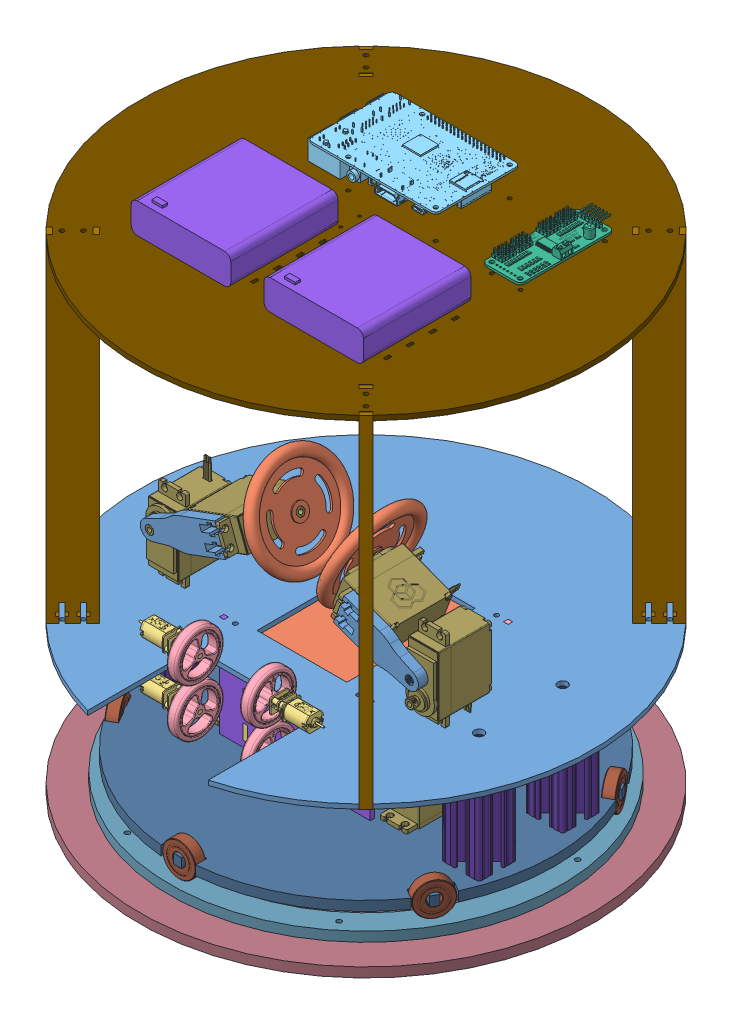
SolidWorks assembly Big_assembly, configuration Default. Lengths in mm.
Overall size (883.19 344.85 416.68).
60 component instances, 26 part files, 69 mates.
Components (placement in the parent):
- Top_Plate-1: Top_Plate [Default] at (43.1232 135.9669 213.6258) size (300 3 294.57)
- Deck-1: Deck [Default] at (43.1232 119.9669 213.6258) size (883.19 16 224.45)
- wall_long_side-1: wall_long_side [Default] at (11.6232 103.9669 213.6258) x (0 0 1) z (-1 0 0) size (94.4 64 3)
- wall_long_side-2: wall_long_side [Default] at (77.6232 103.9669 213.6258) x (0 0 1) z (-1 0 0) size (94.4 64 3)
- wall_back-1: wall_back [Default] at (43.1232 103.9669 166.4258) x (0 0 1) z (-1 0 0) size (3 67 100)
- box_bottom-1: box_bottom [Default] at (43.1232 81.8367 213.6258) size (87.5 3 88)
- Spring-1: Spring [Default] at (81.3732 96.1631 233.6258) size (7.89 47.53 7.89)
- 92125A130_TYPE 18-8 SS FLAT-HEAD SOCKET CAP SCREW-1: 92125A130_TYPE 18-8 SS FLAT-HEAD SOCKET CAP SCREW [92125A130] at (74.6232 132.4669 233.6258) x (0 -0.041478 -0.999139) z (-1 0 0) size (6 6 10.3)
- Spring-2: Spring [Default] at (4.3732 96.1631 233.6258) size (7.89 47.53 7.89)
- Spring-3: Spring [Default] at (81.3732 96.1631 193.6258) size (7.89 47.53 7.89)
- Spring-4: Spring [Default] at (4.3732 96.1631 193.6258) size (7.89 47.53 7.89)
- 92125A130_TYPE 18-8 SS FLAT-HEAD SOCKET CAP SCREW-2: 92125A130_TYPE 18-8 SS FLAT-HEAD SOCKET CAP SCREW [92125A130] at (74.6232 132.4669 193.6258) x (0 -0.041478 -0.999139) z (-1 0 0) size (6 6 10.3)
- 92125A130_TYPE 18-8 SS FLAT-HEAD SOCKET CAP SCREW-3: 92125A130_TYPE 18-8 SS FLAT-HEAD SOCKET CAP SCREW [92125A130] at (11.6232 132.4669 233.6258) x (0 0.041478 0.999139) z (1 0 0) size (6 6 10.3)
- 92125A130_TYPE 18-8 SS FLAT-HEAD SOCKET CAP SCREW-4: 92125A130_TYPE 18-8 SS FLAT-HEAD SOCKET CAP SCREW [92125A130] at (11.6232 132.4669 193.6258) x (0 0.041478 0.999139) z (1 0 0) size (6 6 10.3)
- wall_front_v02-1: wall_front_v02 [Default] at (43.1232 103.9669 260.8258) x (0 0 -1) z (1 0 0) size (3 67 100)
- 220_x_40mm_vertical_beam_1-4_in_t-slots-1: 220_x_40mm_vertical_beam_1-4_in_t-slots [Default] at (129.2665 138.9669 122.9924) x (0.707107 0 -0.707107) z (0 -1 0) size (25 6.35 226)
- assem3-1: assem3 [Default] at (169.2489 77.438 270.0894) x (0.934159 0 0.356856) z (-0.356856 0 0.934159) size (322.75 56.87 322.75)
  - lazy_susan_protoype-1: lazy_susan_protoype [Default] at (-137.9709 -17.8212 -7.7373) x (0.356856 0 0.934159) z (-0.934159 0 0.356856) size (250 6.35 250)
  - 5972K501_BALL BEARING-1: 5972K501_BALL BEARING [5972K501] at (-61.9864 -14.6462 -101.2605) x (-0.500804 -0.763962 -0.406887) z (-0.630577 0 0.776126) size (22 22 7)
  - servo-1: servo [Default] at (-83.0236 -8.9712 -18.0228) x (-0.934159 0 0.356856) z (0.356856 0 0.934159) size (20 45.1 60)
  - servo-2: servo [Default] at (-185.7811 -8.9712 21.2314) x (-0.934159 0 0.356856) z (0.356856 0 0.934159) size (20 45.1 60)
  - 5972K501_BALL BEARING-5: 5972K501_BALL BEARING [5972K501] at (-18.9852 -14.6462 11.3057) x (0.101972 -0.763962 -0.637152) z (-0.987434 0 -0.158033) size (22 22 7)
  - 5972K501_BALL BEARING-6: 5972K501_BALL BEARING [5972K501] at (-94.9697 -14.6462 104.8289) x (0.602776 -0.763962 -0.230265) z (-0.356856 0 -0.934159) size (22 22 7)
  - 5972K501_BALL BEARING-7: 5972K501_BALL BEARING [5972K501] at (-213.9555 -14.6462 85.786) x (0.500804 -0.763962 0.406887) z (0.630577 0 -0.776126) size (22 22 7)
  - base-1: base [Default] at (-137.9709 -38.3462 -7.7373) size (300 6.35 300)
  - new_rail-1: new_rail [Default] at (-137.9709 -31.9962 -7.7373) size (260 6.35 260)
  - new_base_gear-1: new_base_gear [Default] at (-137.9709 -30.0764 -7.7373) x (0 0 -1) z (0 1 0) size (59.22 59.28 6.35)
  - new_servo_gear-1: new_servo_gear [Default] at (-189.3497 -28.8212 11.8898) x (0.783336 0 0.621598) z (0 1 0) size (59.22 59.28 6.35)
  - new_servo_gear-2: new_servo_gear [Default] at (-86.5922 -27.8212 -27.3644) x (0.136575 0 0.99063) z (0 1 0) size (59.22 59.28 6.35)
  - 5972K501_BALL BEARING-8: 5972K501_BALL BEARING [5972K501] at (-256.9567 -14.6462 -26.7802) x (-0.101972 -0.763962 0.637152) z (0.987434 0 0.158033) size (22 22 7)
  - 5972K501_BALL BEARING-9: 5972K501_BALL BEARING [5972K501] at (-180.9721 -14.6462 -120.3035) x (-0.602776 -0.763962 0.230265) z (0.356856 0 0.934159) size (22 22 7)
- 47065T411_ALUMINUM T-SLOTTED FRAMING EXTRUSION-1: 47065T411_ALUMINUM T-SLOTTED FRAMING EXTRUSION [47065T411] at (-59.5768 100.9669 185.9258) x (1 0 0) z (0 -1 0) size (25.4 25.4 70)
- 47065T411_ALUMINUM T-SLOTTED FRAMING EXTRUSION-4: 47065T411_ALUMINUM T-SLOTTED FRAMING EXTRUSION [47065T411] at (-59.5768 100.9669 241.3258) x (1 0 0) z (0 1 0) size (25.4 25.4 70)
- 47065T411_ALUMINUM T-SLOTTED FRAMING EXTRUSION-5: 47065T411_ALUMINUM T-SLOTTED FRAMING EXTRUSION [47065T411] at (145.8232 100.9669 241.3258) x (-1 0 0) z (0 -1 0) size (25.4 25.4 70)
- 47065T411_ALUMINUM T-SLOTTED FRAMING EXTRUSION-6: 47065T411_ALUMINUM T-SLOTTED FRAMING EXTRUSION [47065T411] at (145.8232 100.9669 185.9258) x (-1 0 0) z (0 1 0) size (25.4 25.4 70)
- 220_x_40mm_vertical_beam_1-4_in_t-slots-2: 220_x_40mm_vertical_beam_1-4_in_t-slots [Default] at (133.7566 138.9669 299.7691) x (0.707107 0 0.707107) z (0 -1 0) size (25 6.35 226)
- 220_x_40mm_vertical_beam_1-4_in_t-slots-3: 220_x_40mm_vertical_beam_1-4_in_t-slots [Default] at (-43.0201 138.9669 304.2592) x (-0.707107 0 0.707107) z (0 -1 0) size (25 6.35 226)
- 220_x_40mm_vertical_beam_1-4_in_t-slots-4: 220_x_40mm_vertical_beam_1-4_in_t-slots [Default] at (-47.5102 138.9669 127.4825) x (-0.707107 0 -0.707107) z (0 -1 0) size (25 6.35 226)
- electronics_mount_2-1: electronics_mount_2 [Default] at (-62.9428 358.9669 319.6918) size (300 3.17 300)
- servo-1: servo [Default] at (-43.0683 165.9669 253.4758) x (1 0 0) z (0 -1 0) size (20 45.1 60)
- servo_to_servo_horn-1: servo_to_servo_horn [Default] at (-43.0683 175.9669 264.7258) x (0.937047 0.349203 0) z (0.349203 -0.937047 0) size (56 6.35 20)
- servo-2: servo [Default] at (3.7841 193.427 244.0758) x (0.349203 -0.937047 0) z (0 0 1) size (20 45.1 60)
- 2_5_8_plastic_blue_wheel_futaba_servo_hub-1: 2_5_8_plastic_blue_wheel_futaba_servo_hub [Default] at (18.7909 199.0195 234.0758) x (0.220834 -0.592585 -0.774645) z (-0.937047 -0.349203 0) size (66.67 66.67 7.62)
- micro-metal-gearmotor-backshaft-1: micro-metal-gearmotor-backshaft [Default] at (3.1232 151.9669 302.5558) x (0 0 -1) z (1 0 0) size (12 10.04 40.2)
- pololu-wheel-32x7mm-black-1: pololu-wheel-32x7mm-black [Default] at (18.8232 151.9669 302.5558) x (0 0 -1) z (1 0 0) size (32 32 8.6)
- pololu-wheel-32x7mm-black-2: pololu-wheel-32x7mm-black [Default] at (18.8232 119.9669 302.5558) x (0 0 -1) z (1 0 0) size (32 32 8.6)
- micro-metal-gearmotor-backshaft-2: micro-metal-gearmotor-backshaft [Default] at (3.1232 119.9669 302.5558) x (0 0 -1) z (1 0 0) size (12 10.04 40.2)
- pololu-wheel-32x7mm-black-3: pololu-wheel-32x7mm-black [Default] at (67.4232 151.9669 302.5558) x (0 0 1) z (-1 0 0) size (32 32 8.6)
- micro-metal-gearmotor-backshaft-3: micro-metal-gearmotor-backshaft [Default] at (83.1232 151.9669 302.5558) x (0 0 1) z (-1 0 0) size (12 10.04 40.2)
- pololu-wheel-32x7mm-black-4: pololu-wheel-32x7mm-black [Default] at (67.4232 119.9669 302.5558) x (0 0 1) z (-1 0 0) size (32 32 8.6)
- micro-metal-gearmotor-backshaft-4: micro-metal-gearmotor-backshaft [Default] at (83.1232 119.9669 302.5558) x (0 0 1) z (-1 0 0) size (12 10.04 40.2)
- 2_5_8_plastic_blue_wheel_futaba_servo_hub-2: 2_5_8_plastic_blue_wheel_futaba_servo_hub [Default] at (67.4555 199.0195 234.0758) x (-0.220834 -0.592585 -0.774645) z (-0.937047 0.349203 0) size (66.67 66.67 7.62)
- servo-3: servo [Default] at (82.4624 193.427 244.0758) x (0.349203 0.937047 0) z (0 0 1) size (20 45.1 60)
- servo_to_servo_horn-2: servo_to_servo_horn [Default] at (129.3147 175.9669 271.0758) x (-0.937047 0.349203 0) z (-0.349203 -0.937047 0) size (56 6.35 20)
- servo-4: servo [Default] at (129.3147 171.9669 253.4758) x (-1 0 0) z (0 1 0) size (20 45.1 60)
- raspberryPi3B-1: raspberryPi3B [Detailed] at (33.1232 381.4419 171.8979) x (-1 0 0) z (0 -1 0) size (87.05 58.5 19.5)
- 12Channel PWM-1: 12Channel PWM [Default] at (118.7022 367.1419 168.4479) size (25.4 7.55 66.7)
- RPi cam Rev 1.3-1: RPi cam Rev 1.3 [Výchozí] at (43.1232 352.6669 209.4758) x (-1 0 0) z (0 -1 0) size (25.2 33.1 8.7)
- battery pack-1: battery pack [Default] at (-0.8443 362.1419 256.7519) x (0 0 1) z (-1 0 0) size (71.12 21.5 66.04)
- battery pack-2: battery pack [Default] at (87.1557 362.1419 256.7519) x (0 0 1) z (-1 0 0) size (71.12 21.5 66.04)
Mates (geometry in assembly coordinates):
- Coincident1: coincident anti-aligned: plane of Top_Plate-1 through (43.1232 135.9669 213.6258) normal (0 -1 0); plane of Deck-1 through (43.1232 135.9669 213.6258) normal (0 1 0)
- Symmetric1: symmetric aligned: plane of Top_Plate-1 through (43.1232 135.9669 213.6258) normal (0 0 1); plane of Deck-1 through (11.3732 135.9669 169.1758) normal (0 0 -1); plane of Deck-1 through (11.3732 135.9669 258.0758) normal (0 0 1)
- Symmetric2: symmetric aligned: plane of Top_Plate-1 through (43.1232 135.9669 213.6258) normal (1 0 0); plane of Deck-1 through (74.8732 135.9669 258.0758) normal (1 0 0); plane of Deck-1 through (11.3732 135.9669 258.0758) normal (-1 0 0)
- Coincident2: coincident anti-aligned: plane of Top_Plate-1 through (43.1232 135.9669 213.6258) normal (0 -1 0); plane of wall_long_side-1 through (8.6232 135.9669 166.4258) normal (0 1 0)
- Parallel1: parallel anti-aligned: plane of Deck-1 through (11.3732 135.9669 258.0758) normal (-1 0 0); plane of wall_long_side-1 through (11.6232 103.9669 213.6258) normal (1 0 0)
- Symmetric3: symmetric aligned: plane of Top_Plate-1 through (43.1232 135.9669 213.6258) normal (0 0 1); plane of wall_long_side-1 through (8.6232 115.9669 169.4258) normal (0 0 -1); plane of wall_long_side-1 through (8.6232 115.9669 257.8258) normal (0 0 1)
- Coincident4: coincident anti-aligned: plane of Top_Plate-1 through (43.1232 135.9669 213.6258) normal (0 -1 0); plane of wall_back-1 through (93.1232 135.9669 169.4258) normal (0 1 0)
- Coincident5: coincident anti-aligned: plane of wall_back-1 through (43.1232 103.9669 169.4258) normal (0 0 1); plane of wall_long_side-1 through (8.6232 75.9669 169.4258) normal (0 0 -1)
- Symmetric4: symmetric aligned: plane of Top_Plate-1 through (43.1232 135.9669 213.6258) normal (1 0 0); plane of wall_back-1 through (-6.8768 71.9669 169.4258) normal (-1 0 0); plane of wall_back-1 through (93.1232 71.9669 169.4258) normal (1 0 0)
- Coincident6: coincident anti-aligned: plane of wall_long_side-2 through (74.6232 103.9669 213.6258) normal (-1 0 0); plane of wall_back-1 through (74.6232 125.8669 166.4258) normal (1 0 0)
- Parallel2: parallel anti-aligned: plane of Top_Plate-1 through (43.1232 135.9669 213.6258) normal (0 -1 0); plane of box_bottom-1 through (43.1232 84.8367 213.6258) normal (0 1 0)
- Symmetric6: symmetric aligned: plane of Top_Plate-1 through (43.1232 135.9669 213.6258) normal (0 0 1); plane of box_bottom-1 through (74.3732 84.8367 257.6258) normal (0 0 1); plane of box_bottom-1 through (74.3732 84.8367 169.6258) normal (0 0 -1)
- Symmetric7: symmetric aligned: plane of Top_Plate-1 through (43.1232 135.9669 213.6258) normal (1 0 0); plane of box_bottom-1 through (11.8732 84.8367 169.6258) normal (-1 0 0); plane of box_bottom-1 through (74.3732 84.8367 169.6258) normal (1 0 0)
- Concentric1: concentric anti-aligned: cylinder of wall_long_side-2 through (71.6232 132.4669 233.6258) axis (1 0 0) radius 1.4224; cylinder of 92125A130_TYPE 18-8 SS FLAT-HEAD SOCKET CAP SCREW-1 through (74.6232 132.4669 233.6258) axis (-1 0 0) radius 3
- Coincident10: coincident aligned: plane of wall_long_side-2 through (74.6232 103.9669 213.6258) normal (-1 0 0); plane of 92125A130_TYPE 18-8 SS FLAT-HEAD SOCKET CAP SCREW-1 through (74.6232 133.9656 233.5636) normal (-1 0 0)
- Concentric4: concentric aligned: circle of Spring-1; circle of 92125A130_TYPE 18-8 SS FLAT-HEAD SOCKET CAP SCREW-1
- Parallel4: parallel aligned: plane of wall_long_side-2 through (77.6232 103.9669 213.6258) normal (1 0 0); plane of Spring-1 through (81.3732 96.1631 233.6258) normal (1 0 0)
- Distance1: distance = 3.75 mm aligned: plane of Spring-1 through (81.3732 96.1631 233.6258) normal (1 0 0); plane of wall_long_side-2 through (77.6232 103.9669 213.6258) normal (1 0 0)
- Coincident14: coincident anti-aligned: plane of Top_Plate-1 through (43.1232 135.9669 213.6258) normal (0 -1 0); plane of wall_front_v02-1 through (-6.8768 135.9669 257.8258) normal (0 1 0)
- Parallel5: parallel anti-aligned: plane of Deck-1 through (11.3732 135.9669 258.0758) normal (0 0 1); plane of wall_front_v02-1 through (43.1232 103.9669 257.8258) normal (0 0 -1)
- Symmetric8: symmetric aligned: plane of Top_Plate-1 through (43.1232 135.9669 213.6258) normal (1 0 0); plane of wall_front_v02-1 through (93.1232 71.9669 257.8258) normal (1 0 0); plane of wall_front_v02-1 through (-6.8768 71.9669 257.8258) normal (-1 0 0)
- Coincident16: coincident anti-aligned: plane of wall_long_side-1 through (8.6232 75.9669 257.8258) normal (0 0 1); plane of wall_front_v02-1 through (43.1232 103.9669 257.8258) normal (0 0 -1)
- Coincident17: coincident anti-aligned: plane of Top_Plate-1 through (43.1232 138.9669 213.6258) normal (0 1 0); plane of 220_x_40mm_vertical_beam_1-4_in_t-slots-1 through (140.0657 138.9669 121.1734) normal (0 -1 0)
- Concentric5: concentric aligned: cylinder of Top_Plate-1 through (43.1232 138.9669 213.6258) axis (0 -1 0) radius 150; cylinder of assem3-1/lazy_susan_protoype-1 through (43.1232 65.9669 213.6258) axis (0 -1 0) radius 125
- Parallel6: parallel aligned: plane of wall_long_side-1 through (8.6232 103.9669 213.6258) normal (-1 0 0); plane of assem3-1/servo-2 through (-21.8768 88.4669 243.1258) normal (-1 0 0)
- Coincident20: coincident anti-aligned: plane of assem3-1/lazy_susan_protoype-1 through (43.1232 65.9669 213.6258) normal (0 1 0); plane of 47065T411_ALUMINUM T-SLOTTED FRAMING EXTRUSION-1 through (-65.9932 65.9669 176.516) normal (0 -1 0)
- Parallel7: parallel aligned: plane of wall_long_side-1 through (8.6232 103.9669 213.6258) normal (-1 0 0); plane of 47065T411_ALUMINUM T-SLOTTED FRAMING EXTRUSION-1 through (-72.2768 65.9669 195.4762) normal (-1 0 0)
- Distance4: distance = 25 mm anti-aligned: plane of 47065T411_ALUMINUM T-SLOTTED FRAMING EXTRUSION-1 through (-46.8768 65.9669 176.3754) normal (1 0 0); plane of assem3-1/servo-2 through (-21.8768 88.4669 243.1258) normal (-1 0 0)
- Coincident27: coincident anti-aligned: plane of Top_Plate-1 through (43.1232 135.9669 213.6258) normal (0 -1 0); plane of 47065T411_ALUMINUM T-SLOTTED FRAMING EXTRUSION-1 through (-65.9932 135.9669 176.516) normal (0 1 0)
- Distance6: distance = 15 mm aligned: plane of Top_Plate-1 through (43.1232 135.9669 213.6258) normal (0 0 1); plane of 47065T411_ALUMINUM T-SLOTTED FRAMING EXTRUSION-1 through (-65.9099 65.9669 198.6258) normal (0 0 1)
- Symmetric10: symmetric aligned: plane of Top_Plate-1 through (43.1232 135.9669 213.6258) normal (0.707107 0 0.707107); plane of 220_x_40mm_vertical_beam_1-4_in_t-slots-1 through (133.7566 138.9669 127.4825) normal (0.707107 0 0.707107); plane of 220_x_40mm_vertical_beam_1-4_in_t-slots-1 through (129.2665 138.9669 122.9924) normal (-0.707107 0 -0.707107)
- Tangent6: tangent aligned: cylinder of Top_Plate-1 through (43.1232 138.9669 213.6258) axis (0 -1 0) radius 150; plane of 220_x_40mm_vertical_beam_1-4_in_t-slots-1 through (151.4343 358.9669 109.8048) normal (0.707107 0 -0.707107)
- Coincident28: coincident anti-aligned: plane of 220_x_40mm_vertical_beam_1-4_in_t-slots-4 through (-49.3292 358.9669 116.6833) normal (0 1 0); plane of electronics_mount_2-1 through (-62.9428 358.9669 319.6918) normal (0 -1 0)
- Concentric6: concentric aligned: cylinder of Top_Plate-1 through (43.1232 138.9669 213.6258) axis (0 -1 0) radius 150; cylinder of electronics_mount_2-1 through (43.1232 362.1419 213.6258) axis (0 -1 0) radius 150
- Parallel9: parallel aligned: plane of Deck-1 through (11.3732 135.9669 258.0758) normal (-1 0 0); plane of electronics_mount_2-1 through (36.1557 362.1419 319.6918) normal (-1 0 0)
- Parallel10: parallel aligned: plane of Top_Plate-1 through (43.1232 138.9669 213.6258) normal (0 1 0); plane of servo-1 through (-33.5683 185.9669 233.4758) normal (0 1 0)
- Parallel11: parallel aligned: plane of Top_Plate-1 through (3.1232 135.9669 286.5558) normal (0 0 1); plane of servo-1 through (-43.0683 175.9669 263.9758) normal (0 0 1)
- Coincident31: coincident anti-aligned: plane of Top_Plate-1 through (43.1232 138.9669 213.6258) normal (0 1 0); plane of servo-1 through (-47.0683 138.9669 255.9758) normal (0 -1 0)
- Distance9: distance = 15 mm anti-aligned: plane of servo-1 through (-43.0683 175.9669 271.0758) normal (0 0 1); plane of Top_Plate-1 through (13.3732 138.9669 256.0758) normal (0 0 -1)
- Parallel13: parallel aligned: plane of 47065T411_ALUMINUM T-SLOTTED FRAMING EXTRUSION-4 through (-55.0683 135.9669 242.919) normal (1 0 0); plane of servo-1 through (-33.0683 146.4669 255.9758) normal (1 0 0)
- Coincident34: coincident aligned: plane of servo-1 through (-43.0683 175.9669 271.0758) normal (0 0 1); plane of servo_to_servo_horn-1 through (-15.3421 173.1583 271.0758) normal (0 0 1)
- Concentric7: concentric aligned: circle of servo-1; circle of servo_to_servo_horn-1
- Parallel12: parallel aligned: plane of servo_to_servo_horn-1 through (4.8142 190.6627 271.0758) normal (0.937047 0.349203 0); plane of servo-2 through (15.9657 197.9666 234.0758) normal (0.937047 0.349203 0)
- Coincident36: coincident aligned: plane of servo_to_servo_horn-1 through (-15.3421 173.1583 271.0758) normal (0 0 1); plane of servo-2 through (4.7299 198.0482 271.0758) normal (0 0 1)
- Symmetric11: symmetric anti-aligned: plane of servo_to_servo_horn-1 through (-43.0683 175.9669 264.7258) normal (0.349203 -0.937047 0); line of servo-2 through (2.9839 202.7334 264.0758) axis (0 0 1); line of servo-2 through (9.2695 185.8666 270.0758) axis (0 0 -1)
- Concentric8: concentric anti-aligned: circle of servo-2; circle of 2_5_8_plastic_blue_wheel_futaba_servo_hub-1
- Coincident37: coincident aligned: plane of servo-2 through (20.2761 199.573 234.0758) normal (0.937047 0.349203 0); plane of 2_5_8_plastic_blue_wheel_futaba_servo_hub-1 through (20.2761 199.573 234.0758) normal (0.937047 0.349203 0)
- Coincident38: coincident anti-aligned: plane of servo_to_servo_horn-1 through (1.3222 200.0332 271.0758) normal (0.937047 0.349203 0); plane of servo-2 through (0.4666 202.329 224.5758) normal (-0.937047 -0.349203 0)
- Distance8: distance = 2 mm anti-aligned: plane of servo-1 through (-53.0683 185.4669 233.4758) normal (-1 0 0); plane of 47065T411_ALUMINUM T-SLOTTED FRAMING EXTRUSION-4 through (-55.0683 135.9669 242.919) normal (1 0 0)
- Concentric9: concentric anti-aligned: circle of micro-metal-gearmotor-backshaft-1; circle of pololu-wheel-32x7mm-black-1
- Coincident41: coincident aligned: plane of micro-metal-gearmotor-backshaft-1 through (22.1232 151.9669 302.5558) normal (1 0 0); plane of pololu-wheel-32x7mm-black-1 through (22.1232 151.9669 302.5558) normal (1 0 0)
- Parallel16: parallel anti-aligned: plane of Top_Plate-1 through (43.1232 138.9669 213.6258) normal (0 1 0); plane of micro-metal-gearmotor-backshaft-1 through (-10.8768 146.9669 302.5558) normal (0 -1 0)
- Coincident44: coincident anti-aligned: plane of Top_Plate-1 through (3.1232 135.9669 286.5558) normal (1 0 0); plane of micro-metal-gearmotor-backshaft-1 through (3.1232 146.9669 308.5558) normal (-1 0 0)
- Distance10: distance = 8 mm anti-aligned: plane of micro-metal-gearmotor-backshaft-1 through (-10.8768 146.9669 302.5558) normal (0 -1 0); plane of Top_Plate-1 through (43.1232 138.9669 213.6258) normal (0 1 0)
- Coincident46: coincident anti-aligned: plane of micro-metal-gearmotor-backshaft-1 through (22.1232 152.9669 303.6738) normal (0 1 0); plane of pololu-wheel-32x7mm-black-1 through (13.5232 152.9669 301.4378) normal (0 -1 0)
- Tangent7: tangent anti-aligned: plane of Top_Plate-1 through (3.1232 135.9669 286.5558) normal (0 0 1); cylinder of pololu-wheel-32x7mm-black-1 through (22.1232 151.9669 302.5558) axis (1 0 0) radius 16
- Parallel17: parallel anti-aligned: plane of electronics_mount_2-1 through (-62.9428 362.1419 319.6918) normal (0 1 0); plane of raspberryPi3B-1 through (33.1232 380.1419 171.8979) normal (0 -1 0)
- Concentric10: concentric aligned: cylinder of electronics_mount_2-1 through (72.1232 362.1419 147.3979) axis (0 -1 0) radius 1.25; cylinder of raspberryPi3B-1 through (72.1232 381.4419 147.3979) axis (0 -1 0) radius 1.375
- Distance11: distance = 18 mm anti-aligned: plane of raspberryPi3B-1 through (33.1232 380.1419 171.8979) normal (0 -1 0); plane of electronics_mount_2-1 through (-62.9428 362.1419 319.6918) normal (0 1 0)
- Parallel18: parallel aligned: plane of Top_Plate-1 through (13.3732 138.9669 171.1758) normal (0 0 1); plane of raspberryPi3B-1 through (75.6232 380.1419 199.8979) normal (0 0 1)
- Concentric11: concentric anti-aligned: cylinder of electronics_mount_2-1 through (109.3022 362.1419 196.3979) axis (0 -1 0) radius 1.25; cylinder of 12Channel PWM-1 through (109.3022 363.6063 196.3979) axis (0 1 0) radius 1.25
- Parallel19: parallel anti-aligned: plane of raspberryPi3B-1 through (75.6232 380.1419 143.8979) normal (1 0 0); plane of 12Channel PWM-1 through (106.0022 368.6419 140.4979) normal (-1 0 0)
- Distance12: distance = 5 mm anti-aligned: plane of 12Channel PWM-1 through (128.1022 367.1419 140.4979) normal (0 -1 0); plane of electronics_mount_2-1 through (-62.9428 362.1419 319.6918) normal (0 1 0)
- Concentric12: concentric aligned: cylinder of electronics_mount_2-1 through (32.6232 362.1419 207.3758) axis (0 -1 0) radius 1; cylinder of RPi cam Rev 1.3-1 through (32.6232 353.6669 207.3758) axis (0 -1 0) radius 1.05
- Distance13: distance = 4 mm anti-aligned: plane of RPi cam Rev 1.3-1 through (43.1232 354.9669 209.4758) normal (0 1 0); plane of electronics_mount_2-1 through (-62.9428 358.9669 319.6918) normal (0 -1 0)
- Parallel20: parallel aligned: plane of raspberryPi3B-1 through (9.9232 366.8419 197.6479) normal (0 0 1); plane of RPi cam Rev 1.3-1 through (43.1232 353.6669 221.4758) normal (0 0 1)
- Symmetric12: symmetric aligned: plane of electronics_mount_2-1 through (-35.8443 362.1419 319.6918) normal (-1 0 0); plane of battery pack-1 through (34.1557 362.1419 319.6918) normal (1 0 0); plane of electronics_mount_2-1 through (-0.8443 362.1419 256.7519) normal (-1 0 0)
- Symmetric13: symmetric aligned: plane of electronics_mount_2-1 through (-62.9428 362.1419 277.2519) normal (0 0 1); plane of battery pack-1 through (-62.9428 362.1419 236.2519) normal (0 0 -1); plane of electronics_mount_2-1 through (-0.8443 362.1419 256.7519) normal (0 0 1)
- Coincident54: coincident anti-aligned: plane of electronics_mount_2-1 through (-62.9428 362.1419 319.6918) normal (0 1 0); plane of battery pack-1 through (-0.8443 362.1419 256.7519) normal (0 -1 0)
